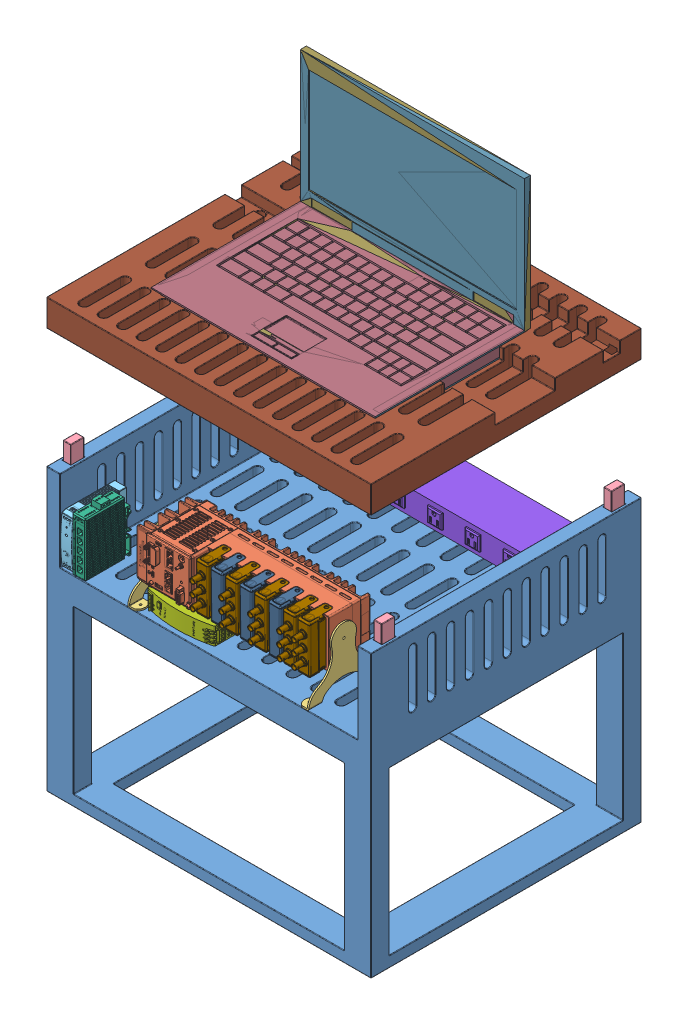
SolidWorks assembly Completo, configuration Valor predeterminado. Lengths in mm.
Overall size (600 1036.12 518.07).
35 component instances, 22 part files, 59 mates.
Components (placement in the parent):
- Base_Reduc_3-1: Base_Reduc_3 [Valor predeterminado] at (-326.4244 0 1082.2527) size (600 520 500)
- compact-1: compact [Valor predeterminado] at (-39.7643 27.5195 800.3638) size (334.85 130.73 132.82)
  - CRIO-1: CRIO [Valor predeterminado] at (-13.3193 107.4805 186.9873) size (328.85 91.42 122.27)
  - SuporteLateral-1: SuporteLateral [Valor predeterminado] at (-130.66 22.4929 151.8888) x (0 0 1) z (-1 0 0) size (130 110 20)
  - SuporteLateral-2: SuporteLateral [Valor predeterminado] at (192.1895 22.4805 281.8888) x (0 0 -1) z (1 0 0) size (130 110 20)
- Pinos-1: Pinos [Valor predeterminado] at (-306.4244 186 1045.0027) x (0 0 1) z (-1 0 0) size (24.5 92 14.5)
- Pinos-2: Pinos [Valor predeterminado] at (-306.4244 186 619.5027) x (0 0 1) z (-1 0 0) size (24.5 92 14.5)
- Pinos-3: Pinos [Valor predeterminado] at (268.0756 186 1045.0027) x (0 0 1) z (-1 0 0) size (24.5 92 14.5)
- Meanwell MDR-20-24.step-1: Meanwell MDR-20-24.step [Valor predeterminado] at (-301.4244 50 981.7527) size (22.94 90 100.5)
- Pinos-4: Pinos [Valor predeterminado] at (268.0756 186 620.0027) x (0 0 1) z (-1 0 0) size (24.5 92 14.5)
- Poe Unmanaged Ethernet Switch EDS-205.stp-1: Poe Unmanaged Ethernet Switch EDS-205.stp [Valor predeterminado] at (-254.3244 50 1008.2527) x (0 0 1) z (-1 0 0) size (87.52 110 25)
- cu_ps-15-1: cu_ps-15 [Valor predeterminado] at (-94.4244 66 1017.2619) x (0 1 0) z (0 0 1) size (32 130.78 122.4)
- RS-1215-RA.step-1: RS-1215-RA.step [Valor predeterminado] at (27.5956 72.225 580.7287) x (1 0 0) z (0 0 -1) size (482.6 44.45 170.72)
- cu_ni-9232_bnc-2: cu_ni-9232_bnc [Valor predeterminado] at (2.3016 135.1691 999.4458) x (1 0.000001 -0.000152) z (0.000152 -0.008727 0.999962) size (24.1 88.43 92.35)
- cu_ni-9232_bnc-3: cu_ni-9232_bnc [Valor predeterminado] at (55.8956 135.1692 999.4377) x (1 0.000001 -0.000152) z (0.000152 -0.008727 0.999962) size (24.1 88.43 92.35)
- cu_ni-9232_bnc-4: cu_ni-9232_bnc [Valor predeterminado] at (109.4896 135.1692 999.4295) x (1 0.000001 -0.000152) z (0.000152 -0.008727 0.999962) size (24.1 88.43 92.35)
- cu_ni-9232_bnc-5: cu_ni-9232_bnc [Valor predeterminado] at (136.2866 135.1693 999.4254) x (1 0.000001 -0.000152) z (0.000152 -0.008727 0.999962) size (24.1 88.43 92.35)
- cu_mod_crio_blank-1: cu_mod_crio_blank [Valor predeterminado] at (-24.4954 134.9913 999.4483) x (1 0.000001 -0.000152) z (0.000152 -0.008727 0.999962) size (24.09 88.43 74.25)
- cu_mod_crio_blank-2: cu_mod_crio_blank [Valor predeterminado] at (29.0986 134.9913 999.4402) x (1 0.000001 -0.000152) z (0.000152 -0.008727 0.999962) size (24.09 88.43 74.25)
- cu_mod_crio_blank-3: cu_mod_crio_blank [Valor predeterminado] at (82.6926 134.9914 999.432) x (1 0.000001 -0.000152) z (0.000152 -0.008727 0.999962) size (24.09 88.43 74.25)
- cu_ni-9232_bnc-6: cu_ni-9232_bnc [Valor predeterminado] at (-51.2924 135.169 999.454) x (1 0.000001 -0.000152) z (0.000152 -0.008727 0.999962) size (24.1 88.43 92.35)
- Base_Reduc_2-1: Base_Reduc_2 [Valor predeterminado] at (-326.4244 421.1179 1082.2527) size (600 50 500)
- laptop_asm.stp-1: laptop_asm.stp [Valor predeterminado] at (-35.9244 451.1179 828.7527) size (414.06 265.03 290.85)
  - LAPTOP_SKEL.stp-1: LAPTOP_SKEL.stp [Valor predeterminado] at origin size (414.01 265.01 287.01)
  - LAPTOP_BASE.stp-1: LAPTOP_BASE.stp [Valor predeterminado] at origin size (414.06 265.03 287.36)
  - LAPTOP_DISPLAY.stp-1: LAPTOP_DISPLAY.stp [Valor predeterminado] at origin size (414.01 265.01 290.51)
- Power Adapter.step-1: Power Adapter.step [Valor predeterminado] at (15.2871 450.8679 594.7527) x (0 0 -1) z (1 0 0) size (101.1 30 171.62)
  - Component1.step-1: Component1.step [Valor predeterminado] at origin size (50.5 8 103.08)
  - CUI PP3-002B_2.5MM PLUG v1.step-1: CUI PP3-002B_2.5MM PLUG v1.step [Valor predeterminado] at (17 12.5 -101.0749) x (-1 0 0) z (0 0 -1) size (8.2 8.2 33.81)
  - LED.step-1: LED.step [Valor predeterminado] at origin size (2 4.75 5.75)
  - Component4.step-1: Component4.step [Valor predeterminado] at origin size (15.19 16.6 12)
  - Power Brick v3.step-1: Power Brick v3.step [Valor predeterminado] at origin size (45 12.5 90)
  - Power Brick v3-0.step-1: Power Brick v3-0.step [Valor predeterminado] at origin size (45 12.5 90)
  - Power Brick v3-1.step-1: Power Brick v3-1.step [Valor predeterminado] at origin size (30 30 25)
  - Power Brick v3-2.step-1: Power Brick v3-2.step [Valor predeterminado] at origin size (42.8 3 111.9)
Mates (geometry in assembly coordinates):
- Coincidente2: coincident: plane of assembly; plane of assembly; plane of Base_Reduc_3-1 through (-326.4244 50 1082.2527) normal (0 1 0); plane of compact-1/SuporteLateral-2 through (152.4252 50 1082.2526) normal (0 -1 0)
- Coincidente14: coincident: plane of assembly; plane of assembly; plane of Base_Reduc_3-1 through (-301.4244 200 582.2527) normal (1 0 0); plane of Meanwell MDR-20-24.step-1 through (-301.4244 140 981.7527) normal (-1 0 0)
- Coincidente15: coincident: plane of assembly; plane of assembly; plane of Base_Reduc_3-1 through (-326.4244 50 1082.2527) normal (0 1 0); plane of Meanwell MDR-20-24.step-1 through (-301.4244 50 981.7527) normal (0 -1 0)
- Tangente15: tangent: plane of assembly; cylinder of assembly; plane of Base_Reduc_3-1 through (-326.4244 50 1082.2527) normal (0 0 1); cylinder of Meanwell MDR-20-24.step-1 through (-278.9244 95 743.2527) axis (-1 0 0) radius 339
- Coincidente21: coincident: plane of assembly; plane of assembly; plane of Meanwell MDR-20-24.step-1 through (-278.9244 50 981.7527) normal (1 0 0); plane of Poe Unmanaged Ethernet Switch EDS-205.stp-1 through (-278.9244 102.0925 1045.2527) normal (-1 0 0)
- Coincidente22: coincident: plane of assembly; plane of assembly; plane of Base_Reduc_3-1 through (-326.4244 50 1082.2527) normal (0 1 0); plane of Poe Unmanaged Ethernet Switch EDS-205.stp-1 through (-254.3244 50 1082.2527) normal (0 -1 0)
- Tangente2: tangent: cylinder of assembly; plane of assembly; cylinder of Meanwell MDR-20-24.step-1 through (-278.9244 95 743.2527) axis (-1 0 0) radius 339; plane of Poe Unmanaged Ethernet Switch EDS-205.stp-1 through (-254.3244 150 1082.2527) normal (0 0 1)
- Coincidente24: coincident: plane of assembly; plane of assembly; plane of Base_Reduc_3-1 through (-326.4244 50 1082.2527) normal (0 1 0); plane of cu_ps-15-1 through (-80.5999 50 1001.7383) normal (0 -1 0)
- Paralelo1: parallel: plane of assembly; plane of assembly; plane of Base_Reduc_3-1 through (-301.4244 200 582.2527) normal (1 0 0); plane of cu_ps-15-1 through (-156.4244 82 961.5119) normal (-1 0 0)
- Coincidente27: coincident: line of assembly; plane of assembly; line of compact-1/SuporteLateral-1 through (-156.4244 50.0124 1069.3569) axis (0 1 0); plane of cu_ps-15-1 through (-156.4244 82 961.5119) normal (-1 0 0)
- Tangente4: tangent: plane of assembly; cylinder of assembly; plane of compact-1/CRIO-1 through (-125.6474 166.1129 1073.0119) normal (0 0 1); cylinder of cu_ps-15-1 through (-94.4244 82 832.2619) axis (0 1 0) radius 240.75
- Coincidente43: coincident: plane of assembly; plane of assembly; plane of Base_Reduc_3-1 through (-326.4244 50 582.2527) normal (0 0 -1); plane of RS-1215-RA.step-1 through (27.5956 72.225 582.2527) normal (0 0 1)
- Coincidente44: coincident: plane of assembly; plane of assembly; plane of Base_Reduc_3-1 through (-326.4244 50 1082.2527) normal (0 1 0); plane of RS-1215-RA.step-1 through (-193.3844 50 675.9787) normal (0 -1 0)
- Coincidente46: coincident: plane of assembly; plane of assembly; plane of compact-1/CRIO-1 through (-6.1383 177.8371 1021.9207) normal (0 0.999962 0.008727); plane of cu_ni-9232_bnc-2 through (2.3058 177.7899 1027.327) normal (0 -0.999962 -0.008727)
- Tangente6: tangent: curve of ?; line of cu_ni-9232_bnc-2 through (-5.3119 177.6589 1042.339) axis (-0.000152 0.008727 -0.999962)
- Coincidente47: coincident: plane of assembly; plane of assembly; plane of compact-1/CRIO-1 through (47.4557 177.8371 1021.9207) normal (0 0.999962 0.008727); plane of cu_ni-9232_bnc-3 through (55.8998 177.79 1027.3188) normal (0 -0.999962 -0.008727)
- Tangente8: tangent: edge_curve of ?; line of cu_ni-9232_bnc-3 through (48.2821 177.659 1042.3308) axis (-0.000152 0.008727 -0.999962)
- Coincidente48: coincident: plane of assembly; plane of assembly; plane of compact-1/CRIO-1 through (101.0497 177.8371 1021.9207) normal (0 0.999962 0.008727); plane of cu_ni-9232_bnc-4 through (109.4938 177.7901 1027.3107) normal (0 -0.999962 -0.008727)
- Tangente9: tangent: edge_curve of ?; line of cu_ni-9232_bnc-4 through (101.8761 177.6591 1042.3227) axis (-0.000152 0.008727 -0.999962)
- Coincidente49: coincident: plane of assembly; plane of assembly; plane of compact-1/CRIO-1 through (127.8467 177.8371 1021.9207) normal (0 0.999962 0.008727); plane of cu_ni-9232_bnc-5 through (136.2908 177.7901 1027.3066) normal (0 -0.999962 -0.008727)
- Tangente10: tangent: edge_curve of ?; line of cu_ni-9232_bnc-5 through (128.6731 177.6591 1042.3186) axis (-0.000152 0.008727 -0.999962)
- Coincidente50: coincident: plane of assembly; plane of assembly; plane of compact-1/CRIO-1 through (-32.9353 177.8371 1021.9207) normal (0 0.999962 0.008727); plane of cu_mod_crio_blank-1 through (-24.4912 177.7899 1027.3311) normal (0 -0.999962 -0.008727)
- Tangente11: tangent: edge_curve of ?; line of cu_mod_crio_blank-1 through (-32.1089 177.6589 1042.3431) axis (-0.000152 0.008727 -0.999962)
- Coincidente51: coincident: plane of assembly; plane of assembly; plane of compact-1/CRIO-1 through (20.6587 177.8371 1021.9207) normal (0 0.999962 0.008727); plane of cu_mod_crio_blank-2 through (29.1028 177.79 1027.3229) normal (0 -0.999962 -0.008727)
- Tangente12: tangent: edge_curve of ?; line of cu_mod_crio_blank-2 through (21.4851 177.6589 1042.3349) axis (-0.000152 0.008727 -0.999962)
- Coincidente52: coincident: plane of assembly; plane of assembly; plane of compact-1/CRIO-1 through (74.2527 177.8371 1021.9207) normal (0 0.999962 0.008727); plane of cu_mod_crio_blank-3 through (82.6968 177.79 1027.3148) normal (0 -0.999962 -0.008727)
- Tangente14: tangent: edge_curve of ?; line of cu_mod_crio_blank-3 through (75.0791 177.659 1042.3268) axis (-0.000152 0.008727 -0.999962)
- Coincidente56: coincident: plane of assembly; plane of assembly; plane of Base_Reduc_3-1 through (248.5756 200 582.2527) normal (-1 0 0); plane of RS-1215-RA.step-1 through (248.5756 94.45 675.9787) normal (1 0 0)
- Distância1: distance = 125 mm: plane of assembly; plane of assembly; plane of compact-1/SuporteLateral-1 through (-176.4244 50.0124 983.1358) normal (-1 0 0); plane of Base_Reduc_3-1 through (-301.4244 200 582.2527) normal (1 0 0)
- Coincidente59: coincident: line of cu_ni-9232_bnc-3 through (59.709 178.6471 1022.2456) axis (-1 -0.000001 0.000152); line of cu_mod_crio_blank-3 through (86.506 178.6471 1022.2415) axis (-1 -0.000001 0.000152)
- Coincidente60: coincident: line of cu_ni-9232_bnc-3 through (59.709 178.6471 1022.2456) axis (-1 -0.000001 0.000152); line of cu_ni-9232_bnc-4 through (113.303 178.6472 1022.2374) axis (-1 -0.000001 0.000152)
- Coincidente61: coincident: line of cu_ni-9232_bnc-3 through (59.709 178.6471 1022.2456) axis (-1 -0.000001 0.000152); line of cu_ni-9232_bnc-5 through (140.1 178.6472 1022.2333) axis (-1 -0.000001 0.000152)
- Coincidente62: coincident: line of cu_ni-9232_bnc-3 through (59.709 178.6471 1022.2456) axis (-1 -0.000001 0.000152); line of cu_mod_crio_blank-2 through (32.912 178.6471 1022.2496) axis (-1 -0.000001 0.000152)
- Coincidente63: coincident: line of cu_ni-9232_bnc-3 through (59.709 178.6471 1022.2456) axis (-1 -0.000001 0.000152); line of cu_ni-9232_bnc-2 through (6.115 178.647 1022.2537) axis (-1 -0.000001 0.000152)
- Coincidente64: coincident: line of cu_ni-9232_bnc-3 through (59.709 178.6471 1022.2456) axis (-1 -0.000001 0.000152); line of cu_mod_crio_blank-1 through (-20.682 178.647 1022.2578) axis (-1 -0.000001 0.000152)
- Coincidente66: coincident: plane of assembly; plane of assembly; plane of compact-1/CRIO-1 through (-59.7323 177.8371 1021.9207) normal (0 0.999962 0.008727); plane of cu_ni-9232_bnc-6 through (-51.2882 177.7898 1027.3352) normal (0 -0.999962 -0.008727)
- Coincidente68: coincident: plane of assembly; plane of assembly; plane of Base_Reduc_3-1 through (-326.4244 50 1082.2527) normal (0 0 1); plane of compact-1/SuporteLateral-1 through (-173.4244 50.0124 1082.2527) normal (0 0 1)
- Paralelo3: parallel: line of cu_mod_crio_blank-1 through (-32.1089 178.4716 1042.3502) axis (-0.000152 0.008727 -0.999962); line of cu_ni-9232_bnc-6 through (-43.6684 178.6137 1026.0712) axis (0.000152 -0.008727 0.999962)
- Coincidente70: coincident: line of cu_mod_crio_blank-1 through (-20.682 178.647 1022.2578) axis (-1 -0.000001 0.000152); line of cu_ni-9232_bnc-6 through (-47.479 178.647 1022.2619) axis (-1 -0.000001 0.000152)
- Tangente18: tangent: edge_curve of ?; line of cu_ni-9232_bnc-6 through (-58.9059 177.6588 1042.3472) axis (-0.000152 0.008727 -0.999962)
- Coincidente71: coincident: plane of assembly; plane of assembly; plane of Base_Reduc_3-1 through (-326.4244 140 1082.2527) normal (0 1 0); plane of Pinos-1 through (-320.9244 140 1057.2527) normal (0 -1 0)
- Coincidente72: coincident: plane of Base_Reduc_3-1 through (-306.4244 140 1057.2527) normal (-1 0 0); plane of Pinos-1 through (-306.4244 186 1045.0027) normal (1 0 0)
- Coincidente73: coincident: plane of Base_Reduc_3-1 through (-321.4244 140 1057.2527) normal (0 0 -1); plane of Pinos-1 through (-320.9244 140 1057.2527) normal (0 0 1)
- Coincidente74: coincident: plane of assembly; plane of assembly; plane of Base_Reduc_3-1 through (-306.4244 140 607.2527) normal (-1 0 0); plane of Pinos-2 through (-306.4244 186 619.5027) normal (1 0 0)
- Coincidente75: coincident: plane of Base_Reduc_3-1 through (-321.4244 140 607.2527) normal (0 0 1); plane of Pinos-2 through (-320.9244 140 607.2527) normal (0 0 -1)
- Coincidente76: coincident: plane of Base_Reduc_3-1 through (-326.4244 140 1082.2527) normal (0 1 0); plane of Pinos-2 through (-320.9244 140 631.7527) normal (0 -1 0)
- Coincidente77: coincident: plane of assembly; plane of assembly; plane of Base_Reduc_3-1 through (253.5756 140 1057.2527) normal (1 0 0); plane of Pinos-3 through (253.5756 186 1045.0027) normal (-1 0 0)
- Coincidente78: coincident: plane of Base_Reduc_3-1 through (-326.4244 140 1082.2527) normal (0 1 0); plane of Pinos-3 through (253.5756 140 1057.2527) normal (0 -1 0)
- Coincidente79: coincident: plane of Base_Reduc_3-1 through (268.5756 140 1057.2527) normal (0 0 -1); plane of Pinos-3 through (253.5756 140 1057.2527) normal (0 0 1)
- Coincidente80: coincident: plane of assembly; plane of assembly; plane of Base_Reduc_3-1 through (253.5756 140 607.2527) normal (1 0 0); plane of Pinos-4 through (253.5756 186 620.0027) normal (-1 0 0)
- Coincidente81: coincident: plane of Base_Reduc_3-1 through (268.5756 140 632.2527) normal (0 0 -1); plane of Pinos-4 through (253.5756 140 632.2527) normal (0 0 1)
- Coincidente82: coincident: plane of Base_Reduc_3-1 through (-326.4244 140 1082.2527) normal (0 1 0); plane of Pinos-4 through (253.5756 140 632.2527) normal (0 -1 0)
- Coincidente84: coincident: plane of Pinos-3 through (253.5756 140 1057.2527) normal (0 0 1); plane of Base_Reduc_2-1 through (-326.4244 456.1179 1057.2527) normal (0 0 -1)
- Coincidente86: coincident: plane of Base_Reduc_2-1 through (171.0756 451.1179 972.2527) normal (0 0 -1); plane of ? through (-242.9244 451.1179 972.2527) normal (0 0 -1)
- Coincidente87: coincident: plane of Base_Reduc_2-1 through (-326.4244 451.1179 1082.2527) normal (0 1 0); plane of ? through (-35.9244 451.1179 828.7527) normal (0 -1 0)
- Coincidente88: coincident: plane of Base_Reduc_2-1 through (171.0756 451.1179 972.2527) normal (-1 0 0); plane of ? through (171.0756 451.1179 972.2527) normal (1 0 0)
- Coincidente89: coincident: plane of Base_Reduc_2-1 through (53.5756 269.9412 594.7527) normal (0 0 1); plane of ? through (15.2871 450.8679 594.7527) normal (0 0 -1)
- Coincidente90: coincident: plane of Base_Reduc_2-1 through (-326.4244 451.1179 1082.2527) normal (0 1 0); plane of ? through (-29.7129 451.1179 617.2527) normal (0 -1 0)
- Coincidente91: coincident: plane of assembly; plane of assembly; plane of Base_Reduc_3-1 through (-326.4244 50 1082.2527) normal (-1 0 0); plane of Base_Reduc_2-1 through (-326.4244 471.1179 1082.2527) normal (-1 0 0)
